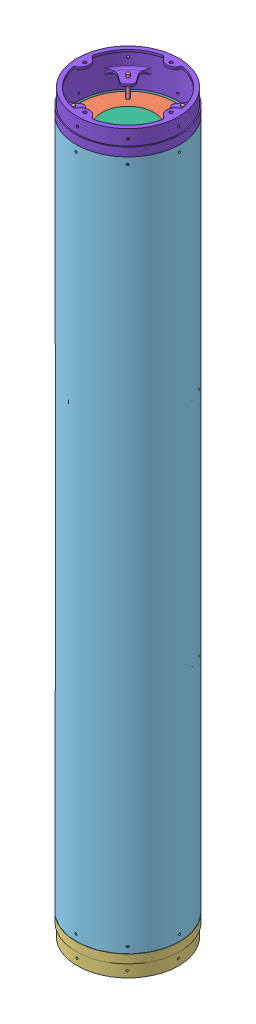
SolidWorks assembly 10005-R02_ASSEMBLY_PRESSURANT_BULK_HEAD (1), configuration Default. Lengths in mm.
Overall size (431.05 2165.35 431.05).
11 component instances, 8 part files, 24 mates.
Components (placement in the parent):
- 15001-R04_PRESSURANT_TANK-1: 15001-R04_PRESSURANT_TANK [Default] x (-0.408985 0 -0.912541) z (0.912541 0 -0.408985) size (266.7 2021.69 266.7)
- 15002-R01_PRESSURANT_TANK_RETAINER-1: 15002-R01_PRESSURANT_TANK_RETAINER [Default] at (-50.7492 1863.09 -92.6521) x (-1 0 0) z (0 0 -1) size (279.4 6.35 279.4)
- 15006-R03_PRESSURANT_TANK_BULKHEAD_BOT-1: 15006-R03_PRESSURANT_TANK_BULKHEAD_BOT [Default] at (0 -187.325 0) x (-0.709743 0 0.704461) z (-0.704461 0 -0.709743) size (304.8 101.6 304.8)
- 16001-R01_THREADED_ROD-1: 16001-R01_THREADED_ROD [Default] at (-80.8223 1856.74 -80.8223) x (-0.419025 0 -0.907975) z (0.907975 0 -0.419025) size (9.53 76.2 9.53)
- 16001-R01_THREADED_ROD-2: 16001-R01_THREADED_ROD [Default] at (-80.8223 1856.74 80.8223) x (0.947021 0 0.32117) z (-0.32117 0 0.947021) size (9.53 76.2 9.53)
- 16001-R01_THREADED_ROD-4: 16001-R01_THREADED_ROD [Default] at (80.8223 1856.74 80.8223) x (-0.974108 0 0.226083) z (-0.226083 0 -0.974108) size (9.53 76.2 9.53)
- 14008_R01_AIRFRAME_SEC2-2: 14008_R01_AIRFRAME_SEC2 [Default] at (0 1908.175 0) x (-0.709743 0 0.704461) z (0 -1 0) size (304.8 304.8 2032)
- 16001-R01_THREADED_ROD-5: 16001-R01_THREADED_ROD [Default] at (80.8223 1856.74 -80.8223) x (-0.780405 0 -0.625275) z (0.625275 0 -0.780405) size (9.53 76.2 9.53)
- 15007-R03_VIBRATION_ABSORBER-1: 15007-R03_VIBRATION_ABSORBER [Default] x (0.369664 0 0.929166) z (-0.929166 0 0.369664) size (152.4 36.62 152.4)
- 15008-R02_LOWER_VIBRATION_ABSORBER-1: 15008-R02_LOWER_VIBRATION_ABSORBER [Default] at (0 1729.74 0) x (-0.910607 0 0.413274) z (0.413274 0 0.910607) size (152.4 36.62 152.4)
- 15005-R05_PRESSURANT_TANK_BULKHEAD_TOP-1: 15005-R05_PRESSURANT_TANK_BULKHEAD_TOP [Default] at (0 1870.075 0) size (304.8 107.95 304.8)
Mates (geometry in assembly coordinates):
- Concentric10: concentric: cylinder of 15001-R04_PRESSURANT_TANK-1 through (0 50.358 0) axis (0 1 0) radius 133.35; cylinder of 15006-R03_PRESSURANT_TANK_BULKHEAD_BOT-1 through (0 -133.35 0) axis (0 1 0) radius 146.05
- Coincident20: coincident: plane of 16001-R01_THREADED_ROD-2 through (-80.8223 1932.94 80.8223) normal (0 1 0); circle of 16001-R01_THREADED_ROD-4
- Concentric24: concentric: cylinder of 15001-R04_PRESSURANT_TANK-1 through (0 50.358 0) axis (0 1 0) radius 133.35; cylinder of 14008_R01_AIRFRAME_SEC2-2 through (0 -123.825 0) axis (0 1 0) radius 152.4
- Coincident24: coincident: plane of 15006-R03_PRESSURANT_TANK_BULKHEAD_BOT-1 through (0 -123.825 0) normal (0 1 0); plane of 14008_R01_AIRFRAME_SEC2-2 through (0 -123.825 0) normal (0 -1 0)
- Concentric25: concentric: cylinder of 15006-R03_PRESSURANT_TANK_BULKHEAD_BOT-1 through (105.9114 -104.775 -105.1232) axis (0.709743 0 -0.704461) radius 3.2639; cylinder of 14008_R01_AIRFRAME_SEC2-2 through (192.1728 -104.775 -190.7427) axis (-0.709743 0 0.704461) radius 3.175
- Coincident30: coincident: plane of 15002-R01_PRESSURANT_TANK_RETAINER-1 through (0 1869.44 0) normal (0 1 0); plane of 15007-R03_VIBRATION_ABSORBER-1 through (-25.821 1869.44 -64.9022) normal (0 -1 0)
- Concentric34: concentric: cylinder of 15002-R01_PRESSURANT_TANK_RETAINER-1 through (0 1869.44 0) axis (0 -1 0) radius 69.85; cylinder of 15007-R03_VIBRATION_ABSORBER-1 through (0 50.358 0) axis (0 1 0) radius 69.85
- Concentric35: concentric: sphere of 15001-R04_PRESSURANT_TANK-1; sphere of 15007-R03_VIBRATION_ABSORBER-1
- Coincident32: coincident: plane of 15006-R03_PRESSURANT_TANK_BULKHEAD_BOT-1 through (0 -139.7 0) normal (0 -1 0); plane of 15008-R02_LOWER_VIBRATION_ABSORBER-1 through (63.6059 -139.7 -28.8672) normal (0 1 0)
- Concentric41: concentric: sphere of 15001-R04_PRESSURANT_TANK-1; sphere of 15008-R02_LOWER_VIBRATION_ABSORBER-1
- Distance1: distance = 6.35 mm: plane of 16001-R01_THREADED_ROD-5 through (80.8223 1856.74 -80.8223) normal (0 -1 0); plane of 15002-R01_PRESSURANT_TANK_RETAINER-1 through (0 1863.09 0) normal (0 -1 0)
- Coincident36: coincident: plane of 16001-R01_THREADED_ROD-4 through (80.8223 1932.94 80.8223) normal (0 1 0); plane of 16001-R01_THREADED_ROD-5 through (80.8223 1932.94 -80.8223) normal (0 1 0)
- Coincident37: coincident: plane of 16001-R01_THREADED_ROD-1 through (-80.8223 1932.94 -80.8223) normal (0 1 0); plane of 16001-R01_THREADED_ROD-5 through (80.8223 1932.94 -80.8223) normal (0 1 0)
- Concentric52: concentric: cylinder of 15002-R01_PRESSURANT_TANK_RETAINER-1 through (80.8223 1869.44 80.8223) axis (0 -1 0) radius 4.7625; cylinder of 16001-R01_THREADED_ROD-4 through (80.8223 1932.94 80.8223) axis (0 -1 0) radius 4.7625
- Concentric53: concentric: cylinder of 15002-R01_PRESSURANT_TANK_RETAINER-1 through (-80.8223 1869.44 80.8223) axis (0 -1 0) radius 4.7625; cylinder of 16001-R01_THREADED_ROD-2 through (-80.8223 1932.94 80.8223) axis (0 -1 0) radius 4.7625
- Concentric54: concentric: cylinder of 15002-R01_PRESSURANT_TANK_RETAINER-1 through (80.8223 1869.44 -80.8223) axis (0 -1 0) radius 4.7625; cylinder of 16001-R01_THREADED_ROD-5 through (80.8223 1932.94 -80.8223) axis (0 -1 0) radius 4.7625
- Concentric55: concentric: cylinder of 15002-R01_PRESSURANT_TANK_RETAINER-1 through (-80.8223 1869.44 -80.8223) axis (0 -1 0) radius 4.7625; cylinder of 16001-R01_THREADED_ROD-1 through (-80.8223 1932.94 -80.8223) axis (0 -1 0) radius 4.7625
- Coincident40: coincident: plane of 15001-R04_PRESSURANT_TANK-1 through (0 0 0) normal (0 1 0); plane of assembly through (0 0 0) normal (0 1 0)
- Concentric56: concentric: cylinder of 16001-R01_THREADED_ROD-5 through (80.8223 1932.94 -80.8223) axis (0 -1 0) radius 4.7625; cylinder of 15005-R05_PRESSURANT_TANK_BULKHEAD_TOP-1 through (80.8223 1924.05 -80.8223) axis (0 1 0) radius 4.7625
- Concentric57: concentric: cylinder of 16001-R01_THREADED_ROD-1 through (-80.8223 1932.94 -80.8223) axis (0 -1 0) radius 4.7625; cylinder of 15005-R05_PRESSURANT_TANK_BULKHEAD_TOP-1 through (-80.8223 1924.05 -80.8223) axis (0 1 0) radius 4.7625
- Concentric58: concentric: cylinder of 16001-R01_THREADED_ROD-2 through (-80.8223 1932.94 80.8223) axis (0 -1 0) radius 4.7625; cylinder of 15005-R05_PRESSURANT_TANK_BULKHEAD_TOP-1 through (-80.8223 1924.05 80.8223) axis (0 1 0) radius 4.7625
- Concentric59: concentric: cylinder of 16001-R01_THREADED_ROD-4 through (80.8223 1932.94 80.8223) axis (0 -1 0) radius 4.7625; cylinder of 15005-R05_PRESSURANT_TANK_BULKHEAD_TOP-1 through (80.8223 1924.05 80.8223) axis (0 1 0) radius 4.7625
- Coincident41: coincident: plane of 14008_R01_AIRFRAME_SEC2-2 through (0 1908.175 0) normal (0 1 0); plane of 15005-R05_PRESSURANT_TANK_BULKHEAD_TOP-1 through (0 1908.175 0) normal (0 -1 0)
- Parallel1: parallel: cylinder of 14008_R01_AIRFRAME_SEC2-2 through (135.206 1889.125 -134.1998) axis (-0.709743 0 0.704461) radius 3.175; cylinder of 15005-R05_PRESSURANT_TANK_BULKHEAD_TOP-1 through (105.9114 1889.1274 -105.1232) axis (0.709743 0 -0.704461) radius 3.2639
